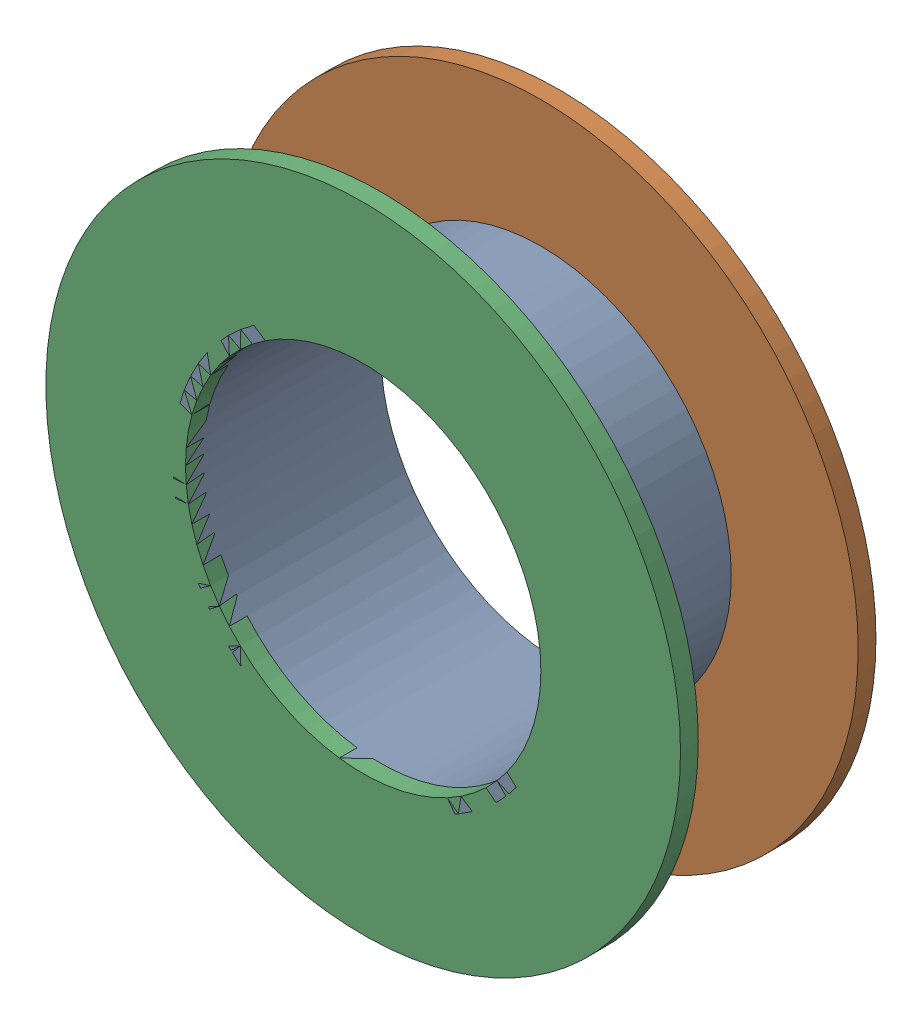
SolidWorks assembly Via (19.1mm,28.2mm) from Top Layer to Bottom Layer, configuration Predeterminado. Lengths in mm.
Overall size (1.27 1.27 0.39).
6 component instances, 2 part files, 0 mates.
Components (placement in the parent):
- Via Hole-1: Via Hole [Predeterminado] at (19.1 28.2 -0.4013) size (0.76 0.76 0.39)
  - Via Hole-Part-1-1: Via Hole-Part-1 [Predeterminado] at origin size (0.76 0.76 0.39)
- Via Top Layer-1: Via Top Layer [Predeterminado] at (19.1 28.2 -0.4013) size (1.27 1.27 0.04)
  - Via Top Layer-Part-1-1: Via Top Layer-Part-1 [Predeterminado] at origin size (1.27 1.27 0.04)
- Via Top Layer-2: Via Top Layer [Predeterminado] at (19.1 28.2 -0.0457) size (1.27 1.27 0.04)
  - Via Top Layer-Part-1-1: Via Top Layer-Part-1 [Predeterminado] at origin size (1.27 1.27 0.04)
